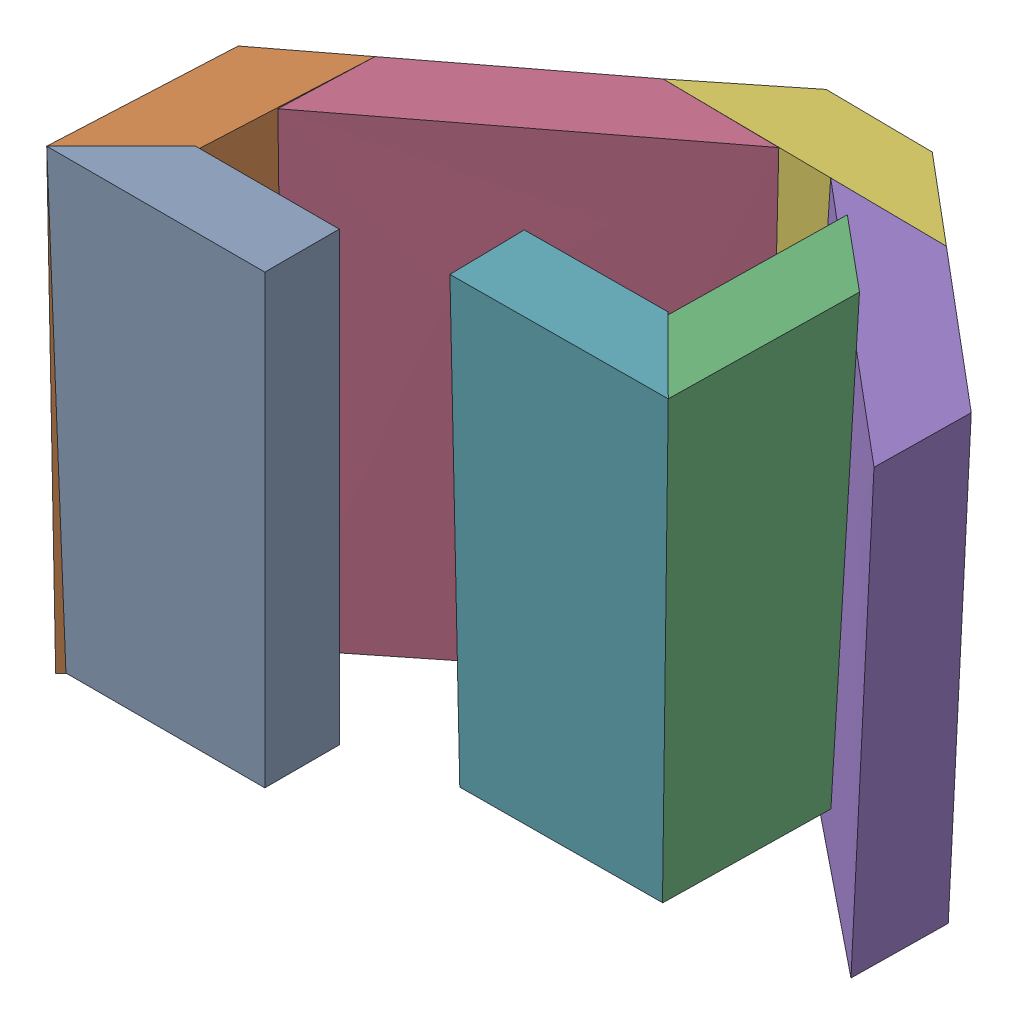
SolidWorks assembly molde_cabeza_2grado, configuration Predeterminado. Lengths in mm.
Overall size (145.25 134.77 118.76).
7 component instances, 7 part files, 3 mates.
Components (placement in the parent):
- molde_cabeza_p0-1: molde_cabeza_p0 [Predeterminado] at (-44.1447 -32.9235 6.25) size (36.62 75 12.5)
- molde_cabeza_p2-1: molde_cabeza_p2 [Predeterminado] at (-31.883 -34.8168 -31.6627) x (-0.999994 0.003376 -0.000644) z (0.000487 -0.046407 -0.998923) size (15.12 75 42.67)
- molde_cabeza_p3-1: molde_cabeza_p3 [Predeterminado] at (95.6069 22.7034 45.2286) x (-0.999984 -0.00534 0.001858) z (-0.001761 -0.018143 -0.999834) size (15.12 75 42.67)
- molde_cabeza_p4-1: molde_cabeza_p4 [Predeterminado] at (-30.1178 -34.3733 -16.9722) x (0.999922 -0.012401 0.001214) z (-0.000782 0.034805 0.999394) size (48.39 75 38.86)
- molde_cabeza_p5-1: molde_cabeza_p5 [Predeterminado] at (18.5038 -36.2876 -54.8008) x (0.999944 -0.010524 0.000859) z (-0.000726 0.012634 0.99992) size (46.71 75 38.69)
- molde_cabeza_p6-1: molde_cabeza_p6 [Predeterminado] at (-7.7447 -36.0073 -54.8235) x (0.999943 -0.01061 0.000863) z (-0.000729 0.012634 0.99992) size (47.61 75 15.12)
- molde_cabeza_p1-1: molde_cabeza_p1 [Predeterminado] at (61.6087 22.5672 45.2662) x (0.999985 0.005348 -0.001086) z (0.001175 -0.016751 0.999859) size (36.62 75 12.5)
Mates (geometry in assembly coordinates):
- Distancia8: distance = 0 mm: point of molde_cabeza_p1-1; point of molde_cabeza_p3-1
- Distancia11: distance = 0 mm: point of molde_cabeza_p3-1; point of molde_cabeza_p1-1
- Distancia13: distance = 0 mm: point of molde_cabeza_p1-1; point of molde_cabeza_p3-1
